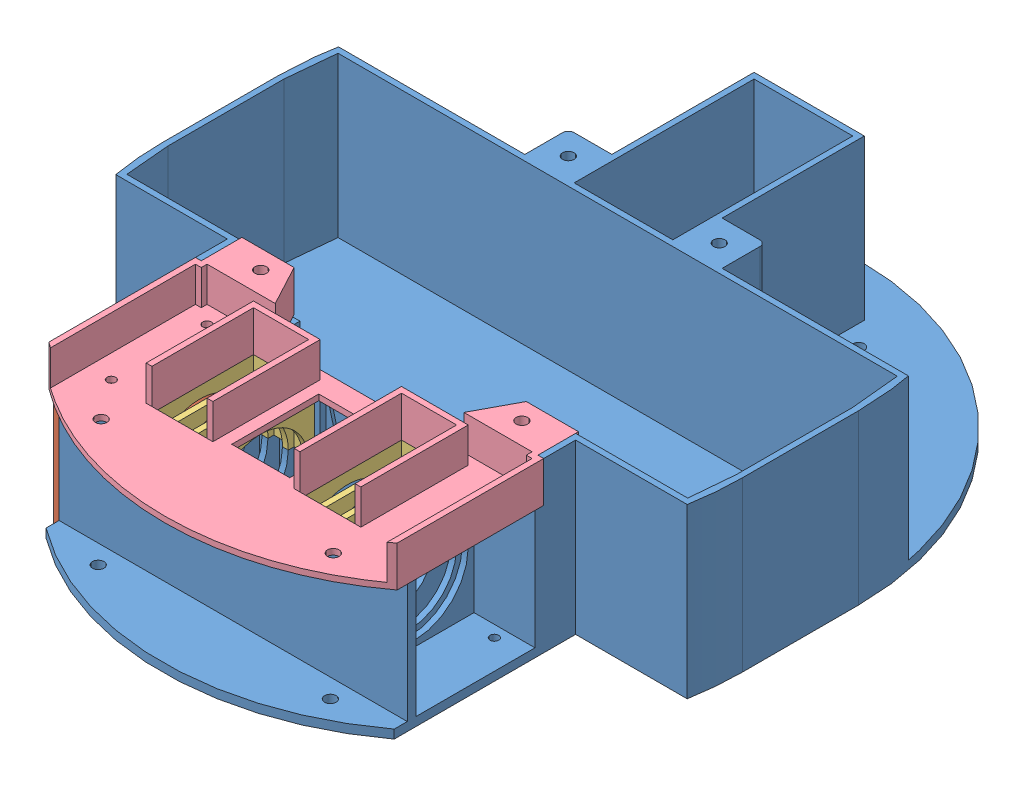
SolidWorks assembly 组装_底盘, configuration 默认. Lengths in mm.
Overall size (200 67 240).
5 component instances, 4 part files, 12 mates.
Components (placement in the parent):
- 小车底盘Pro-1: 小车底盘Pro [默认] at (12.5491 -35.762 260) size (200 67 240)
- 电机安装架-1: 电机安装架 [默认] at (-47.4509 -12.262 312) x (0 0 1) z (-1 0 0) size (57 44 24)
- 电机锁架-1: 电机锁架 [默认] at (-26.4509 8.238 291.5) x (1 0 0) z (0 0 -1) size (25 20.5 41)
- 电机锁架-5: 电机锁架 [默认] at (51.5491 8.238 332.5) x (-1 0 0) z (0 0 1) size (25 20.5 41)
- 电机压板-1: 电机压板 [默认] at (12.5491 8.238 259) size (120 14 84.5)
Mates (geometry in assembly coordinates):
- 重合1: coincident anti-aligned: plane of 小车底盘Pro-1 through (-47.4509 8.238 291.5) normal (0 0 1); plane of 电机安装架-1 through (-26.4509 -12.262 291.5) normal (0 0 -1)
- 重合2: coincident aligned: plane of 小车底盘Pro-1 through (12.5491 8.238 260) normal (0 1 0); plane of 电机安装架-1 through (-50.4509 8.238 277.5) normal (0 1 0)
- 重合3: coincident anti-aligned: plane of 小车底盘Pro-1 through (-47.4509 -35.762 260) normal (-1 0 0); plane of 电机安装架-1 through (-47.4509 -12.262 312) normal (1 0 0)
- 重合4: coincident anti-aligned: plane of 电机安装架-1 through (-26.4509 -12.262 312) normal (1 0 0); plane of 电机锁架-1 through (-26.4509 6.238 291.5) normal (-1 0 0)
- 重合5: coincident aligned: plane of 小车底盘Pro-1 through (12.5491 8.238 260) normal (0 1 0); plane of 电机锁架-1 through (-26.4509 8.238 291.5) normal (0 1 0)
- 重合6: coincident anti-aligned: plane of 小车底盘Pro-1 through (-47.4509 8.238 291.5) normal (0 0 1); plane of 电机锁架-1 through (-26.4509 6.238 291.5) normal (0 0 -1)
- 重合8: coincident: plane of 小车底盘Pro-1 through (12.5491 8.238 260) normal (0 1 0); plane of 电机锁架-5 through (51.5491 8.238 332.5) normal (0 1 0)
- 重合9: coincident: plane of 小车底盘Pro-1 through (26.5491 -12.262 291.5) normal (-1 0 0); plane of 电机锁架-5 through (26.5491 6.238 332.5) normal (-1 0 0)
- 重合10: coincident anti-aligned: plane of 小车底盘Pro-1 through (-47.4509 8.238 291.5) normal (0 0 1); plane of 电机锁架-5 through (51.5491 6.238 291.5) normal (0 0 -1)
- 重合11: coincident: plane of 小车底盘Pro-1 through (12.5491 8.238 260) normal (0 1 0); plane of 电机压板-1 through (12.5491 8.238 259) normal (0 -1 0)
- 重合12: coincident: plane of 小车底盘Pro-1 through (70.5491 22.238 260) normal (-1 0 0); plane of 电机压板-1 through (70.5491 10.238 259) normal (1 0 0)
- 重合13: coincident anti-aligned: plane of 小车底盘Pro-1 through (12.5491 22.238 288.5) normal (0 0 1); plane of 电机压板-1 through (12.5491 10.238 288.5) normal (0 0 -1)
